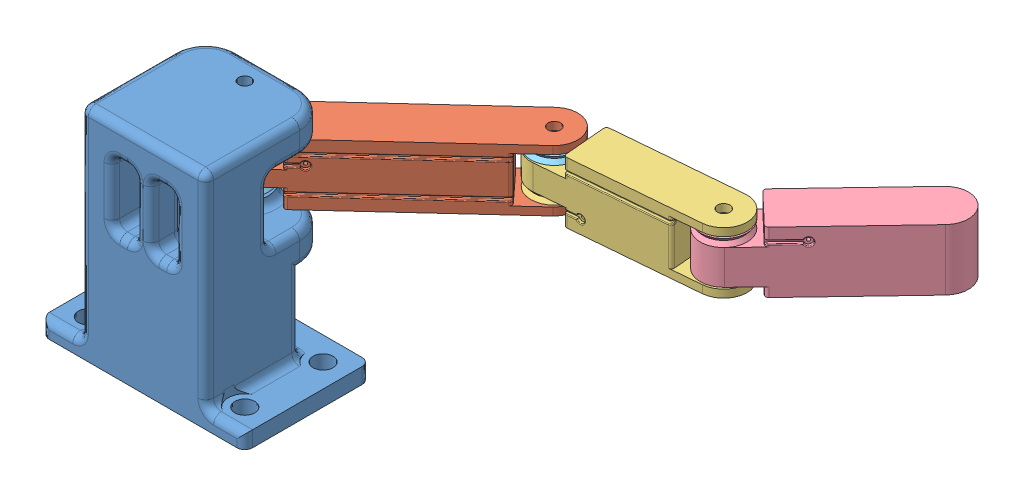
SolidWorks assembly asm, configuration 기본. Lengths in mm.
Overall size (178.91 70.25 131.04).
7 component instances, 5 part files, 13 mates.
Components (placement in the parent):
- base_v1-1: base_v1 [기본] at (-2.084 -21.1326 70.25) size (65 70.25 40.05)
- link1-1: link1 [기본] at (-2.084 25.1174 57.75) x (0.677022 0 0.735963) z (-0.735963 0 0.677022) size (15 19.5 85)
- link2-1: link2 [기본] at (49.4334 24.6174 10.3585) x (0.086581 0 0.996245) z (-0.996245 0 0.086581) size (15 19.5 65)
- link3-1: link3 [기본] at (99.2457 22.1174 6.0294) x (0.724253 0 0.689534) z (-0.689534 0 0.724253) size (15 19.5 65)
- pulley-1: pulley [기본] at (-2.084 33.1174 57.75) x (1 0 0.000007) z (-0.000007 0 1) size (15 2.5 15)
- pulley-2: pulley [기본] at (-2.084 22.1174 57.75) size (15 2.5 15)
- pulley-3: pulley [기본] at (49.4335 33.1174 10.3585) x (0.989305 0 0.14586) z (-0.14586 0 0.989305) size (15 2.5 15)
Mates (geometry in assembly coordinates):
- 동심1: concentric aligned: cylinder of base_v1-1 through (-2.084 2.9606 57.75) axis (0 1 0) radius 2; cylinder of link1-1 through (-2.084 14.9351 57.75) axis (0 1 0) radius 3.6
- 거리1: distance = 0.5 mm anti-aligned: plane of pulley-1 through (-9.584 33.1174 57.7499) normal (0 -1 0); plane of link1-1 through (-2.084 32.6174 57.75) normal (0 1 0)
- 거리2: distance = 0.5 mm anti-aligned: plane of pulley-2 through (-2.084 24.6174 57.75) normal (0 1 0); plane of link1-1 through (-2.084 25.1174 57.75) normal (0 -1 0)
- 거리3: distance = 0.5 mm anti-aligned: plane of link2-1 through (49.4334 22.1174 10.3585) normal (0 -1 0); plane of link1-1 through (-2.084 21.6174 57.75) normal (0 1 0)
- 거리4: distance = 0.5 mm anti-aligned: plane of pulley-3 through (42.0137 33.1174 9.2645) normal (0 -1 0); plane of link2-1 through (49.4334 32.6174 10.3585) normal (0 1 0)
- 동심6: concentric aligned: cylinder of link2-1 through (99.2457 13.4606 6.0294) axis (0 1 0) radius 2; cylinder of link3-1 through (99.2457 11.9351 6.0294) axis (0 1 0) radius 3.6
- 거리5: distance = 0.5 mm anti-aligned: plane of link3-1 through (99.2457 35.6174 6.0294) normal (0 1 0); plane of link2-1 through (49.4334 36.1174 10.3585) normal (0 -1 0)
- 거리6: distance = 1 mm anti-aligned: plane of pulley-1 through (-2.084 35.6174 57.75) normal (0 1 0); plane of base_v1-1 through (-2.084 36.6174 57.75) normal (0 -1 0)
- 동심7: concentric aligned: cylinder of link1-1 through (49.4334 44.2743 10.3585) axis (0 -1 0) radius 2; cylinder of link2-1 through (49.4334 42.7998 10.3585) axis (0 -1 0) radius 3.6
- 동심8: concentric aligned: cylinder of link2-1 through (99.2457 13.4606 6.0294) axis (0 1 0) radius 2; cylinder of link3-1 through (99.2457 11.9351 6.0294) axis (0 1 0) radius 3.6
- 동심10: concentric aligned: cylinder of link1-1 through (-2.084 14.9351 57.75) axis (0 1 0) radius 3.6; cylinder of pulley-1 through (-2.084 22.9351 57.75) axis (0 1 0) radius 3.6
- 동심11: concentric aligned: cylinder of link1-1 through (-2.084 14.9351 57.75) axis (0 1 0) radius 3.6; cylinder of pulley-2 through (-2.084 11.9351 57.75) axis (0 1 0) radius 3.6
- 동심12: concentric anti-aligned: cylinder of link2-1 through (49.4334 42.7998 10.3585) axis (0 -1 0) radius 3.6; cylinder of pulley-3 through (49.4335 22.9351 10.3585) axis (0 1 0) radius 3.6
